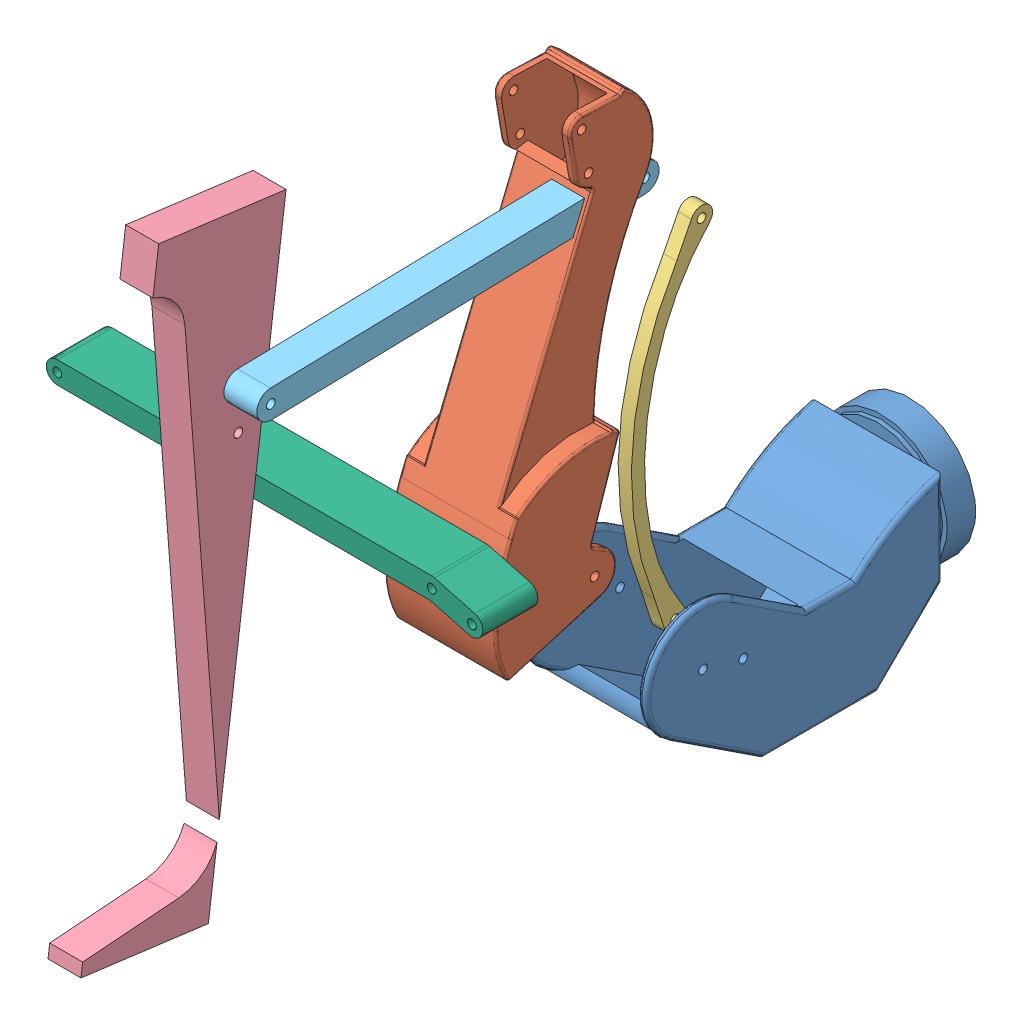
SolidWorks assembly ECM, configuration Default. Lengths in mm.
Overall size (397 593.49 781.38).
6 component instances, 6 part files, 4 mates.
Components (placement in the parent):
- ECM_yaw-1: ECM_yaw [Default] at (136.0744 220.0559 173.8942) size (120.45 158 299.6)
- ECM_1-1: ECM_1 [Default] at (144.8167 291.0621 469.1069) x (0 -0.282822 0.959172) z (-1 0 0) size (246.13 357.8 101)
- ECM_Front-1: ECM_Front [Default] at (134.0744 519.2948 398.6839) x (0 -0.389602 -0.920983) z (-1 0 0) size (121.15 309.18 12)
- ECM_3-1: ECM_3 [Default] at (94.0744 261.1748 462.0918) x (0 -0.131988 0.991251) z (-1 0 0) size (254.53 559 30)
- ECM_top-1: ECM_top [Default] at (94.0744 561.4698 402.5222) x (0 -0.023477 0.999724) z (1 0 0) size (365.93 25.53 30)
- ECM_2a-3: ECM_2a [Default] at (74.9978 92.9505 593.6751) size (397 29.8 50)
Mates (geometry in assembly coordinates):
- Concentric4: concentric anti-aligned: cylinder of ECM_yaw-1 through (207.3881 210.2719 385.3242) axis (-1 0 0) radius 4; cylinder of ECM_Front-1 through (122.0744 210.2719 385.3242) axis (1 0 0) radius 4
- Concentric6: concentric anti-aligned: cylinder of ECM_3-1 through (64.0744 553.4783 742.8284) axis (1 0 0) radius 4; cylinder of ECM_top-1 through (124.0744 553.4783 742.8284) axis (-1 0 0) radius 4
- Concentric13: concentric anti-aligned: cylinder of ECM_3-1 through (64.0744 553.4783 742.8284) axis (1 0 0) radius 4; cylinder of ECM_top-1 through (124.0744 553.4783 742.8284) axis (-1 0 0) radius 4
- Coincident7: coincident anti-aligned: plane of ECM_3-1 through (94.0744 261.1748 462.0918) normal (1 0 0); plane of ECM_top-1 through (94.0744 561.4698 402.5222) normal (-1 0 0)
